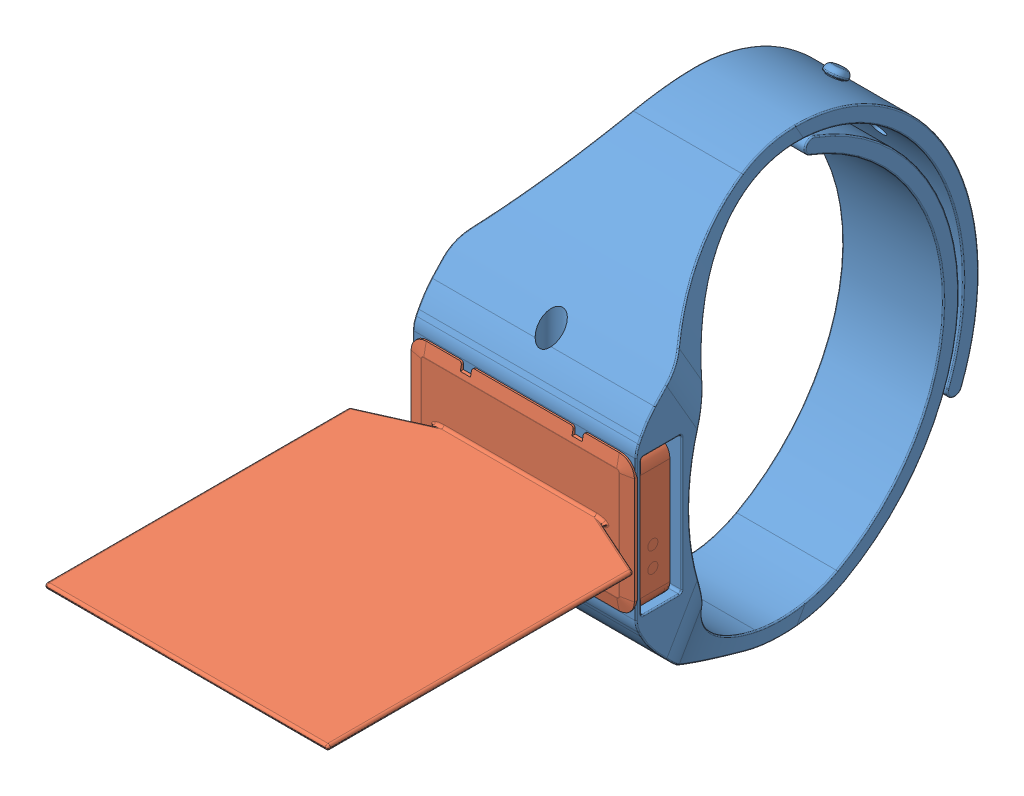
SolidWorks assembly Assemblage1, configuration Défaut. Lengths in mm.
Overall size (55.81 89.96 149.44).
2 component instances, 2 part files, 2 mates.
Components (placement in the parent):
- 3-Part-2-1: 3-Part-2 [Default] at (58.2037 -0.4147 58.2662) size (47.52 89.96 82.82)
- 3-Part-1-1: 3-Part-1 [Default] at (58.2037 -0.3147 60.0909) size (55.81 28.1 73.79)
Mates (geometry in assembly coordinates):
- Coïncidente1: coincident aligned: plane of 3-Part-2-1 through (55.7037 -11.4147 15.7662) normal (-1 0 0); plane of 3-Part-1-1 through (55.7037 -21.3147 56.0909) normal (-1 0 0)
- Distance1: distance = 0.1 mm anti-aligned: plane of 3-Part-1-1 through (96.2037 -24.8147 56.0909) normal (0 -1 0); plane of 3-Part-2-1 through (59.2037 -24.9147 54.2662) normal (0 1 0)
